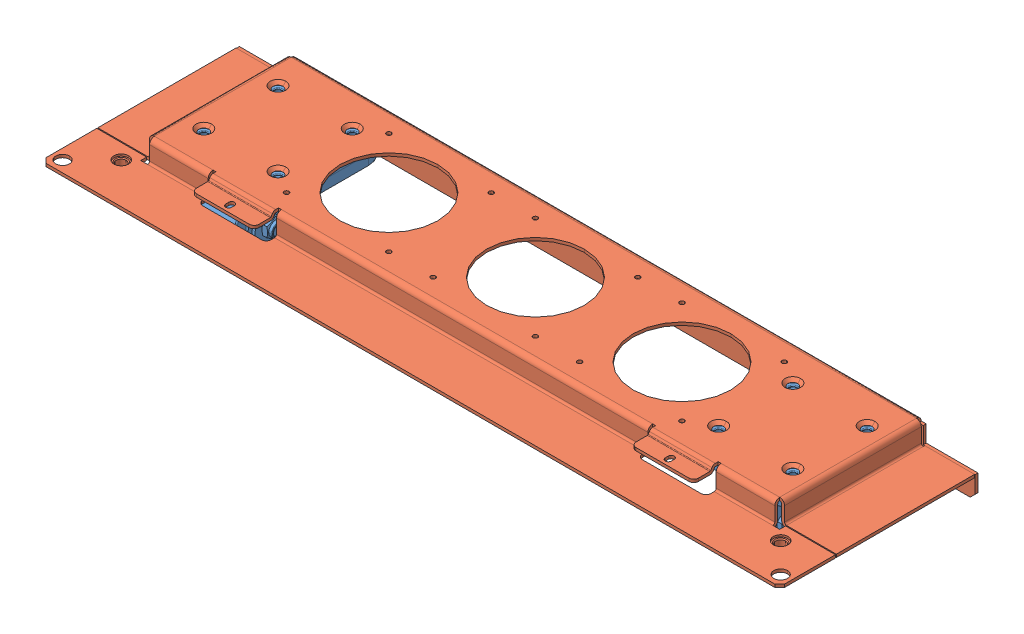
SolidWorks assembly 5301_518, configuration Default. Lengths in mm.
Overall size (756 94.75 203).
3 component instances, 2 part files, 9 mates.
Components (placement in the parent):
- 5301_518-wheel-1: 5301_518-wheel [Default] at (114.5 -6.168 75) x (0 0 -1) z (1 0 0) size (126.74 91.75 114.3)
- 5301_518-wheel-2: 5301_518-wheel [Default] at (641.5 -6.168 75) x (0 0 -1) z (1 0 0) size (126.74 91.75 114.3)
- 5301_518-base-1: 5301_518-base [Default] at (378 0 0) size (756 44.5 203)
Mates (geometry in assembly coordinates):
- Tangential1: tangent: torus of 5301_518-wheel-2; plane of 5301_518-base-1 through (751.5398 -3 145) normal (0 -1 0)
- Tangential2: tangent: torus of 5301_518-wheel-1; plane of 5301_518-base-1 through (751.5398 -3 145) normal (0 -1 0)
- Konzentrisch1: concentric aligned: cylinder of 5301_518-wheel-1 through (130.0398 -17.827 37) axis (0 -1 0) radius 3.3235; circle of 5301_518-base-1
- Konzentrisch2: concentric aligned: cylinder of 5301_518-wheel-1 through (206.0398 -17.827 113) axis (0 -1 0) radius 3.3235; circle of 5301_518-base-1
- Konzentrisch3: concentric aligned: cylinder of 5301_518-wheel-2 through (657.0398 -17.827 113) axis (0 -1 0) radius 3.3235; circle of 5301_518-base-1
- Konzentrisch4: concentric aligned: cylinder of 5301_518-wheel-2 through (733.0398 -17.827 37) axis (0 -1 0) radius 3.3235; circle of 5301_518-base-1
- Deckungsgleich1: coincident anti-aligned: plane of 5301_518-base-1 through (698 -44.5 0) normal (0 0 -1); plane of assembly
- Deckungsgleich2: coincident aligned: plane of 5301_518-base-1 through (698 0 5) normal (0 1 0); plane of assembly
- Deckungsgleich3: coincident anti-aligned: plane of 5301_518-base-1 through (0 -21.5 145) normal (-1 0 0); plane of assembly
